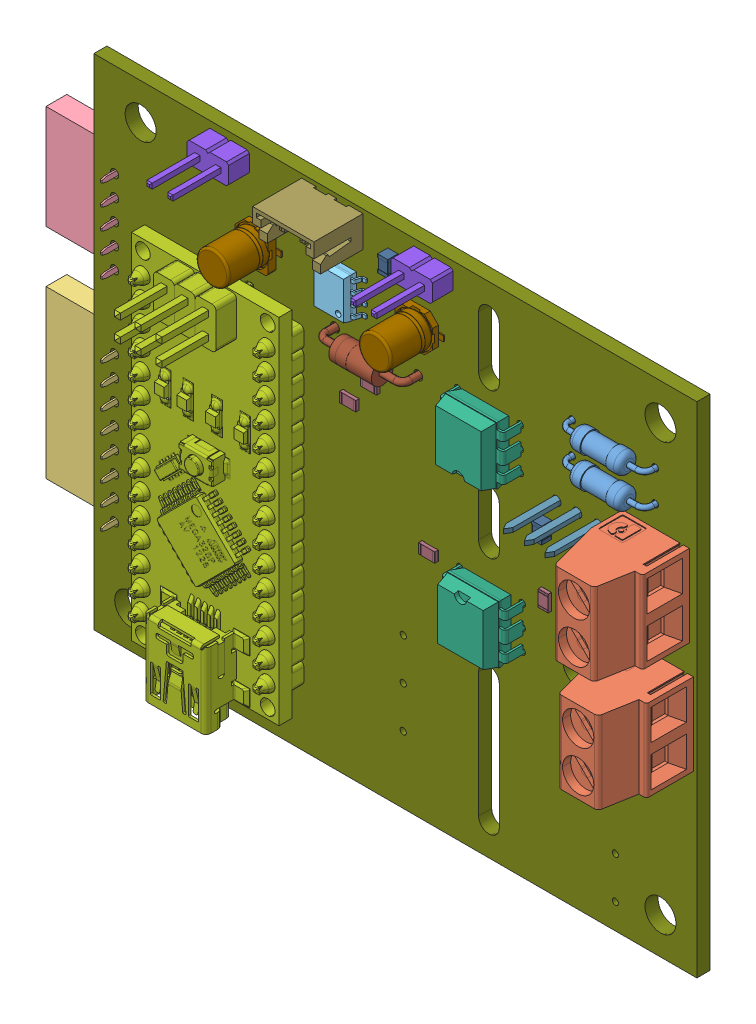
SolidWorks assembly ReflowControllerREV1, configuration Default. Lengths in mm.
Overall size (81.15 60.96 18.6).
74 component instances, 16 part files, 0 mates.
Components (placement in the parent):
- ReflowControllerREV1.step-1: ReflowControllerREV1.step [Default] at origin size (81.15 60.96 18.6)
  - R_Axial_DIN0207_L6.3mm_D2.5mm_P10.16mm_Horizontal.step-1: R_Axial_DIN0207_L6.3mm_D2.5mm_P10.16mm_Horizontal.step [Default] at (251.46 -86.995 1.65) x (-1 0 0) z (0 0 1) size (10.76 2.5 5.5)
    - SOLID.step-1: SOLID.step [Default] at origin size (10.76 2.5 5.5)
  - R_Axial_DIN0207_L6.3mm_D2.5mm_P10.16mm_Horizontal.step-2: R_Axial_DIN0207_L6.3mm_D2.5mm_P10.16mm_Horizontal.step [Default] at (251.46 -83.185 1.65) x (-1 0 0) z (0 0 1) size (10.76 2.5 5.5)
    - SOLID.step-1: SOLID.step [Default] at origin size (10.76 2.5 5.5)
  - Terminal5mmx2.step-1: Terminal5mmx2.step [Default] at (255.095 -100.155 1.65) x (1 0 0) z (0 -1 0) size (8.15 13.5 10.57)
    - SOLID-0.step-1: SOLID-0.step [Default] at origin size (8.15 13.5 10.57)
  - Terminal5mmx2.step-2: Terminal5mmx2.step [Default] at (255.595 -113.49 1.65) x (1 0 0) z (0 -1 0) size (8.15 13.5 10.57)
    - SOLID-0.step-1: SOLID-0.step [Default] at origin size (8.15 13.5 10.57)
  - PinSocket_1x08_P2.54mm_Horizontal.step-1: PinSocket_1x08_P2.54mm_Horizontal.step [Default] at (185.42 -121.92 -0.05) x (1 0 0) z (0 0 -1) size (10.13 20.32 5.84)
    - SOLID-1.step-1: SOLID-1.step [Default] at origin size (10.13 20.32 5.84)
  - PinSocket_1x05_P2.54mm_Horizontal.step-1: PinSocket_1x05_P2.54mm_Horizontal.step [Default] at (185.42 -95.25 -0.05) x (1 0 0) z (0 0 -1) size (10.13 12.7 5.84)
    - SOLID-2.step-1: SOLID-2.step [Default] at origin size (10.13 12.7 5.84)
  - SOIC-8_3,9x4,9.step-1: SOIC-8_3,9x4,9.step [Default] at (213.36 -82.804 1.65) x (0 1 0) z (0 0 1) size (4.9 6 1.75)
    - SOLID-3.step-1: SOLID-3.step [Default] at origin size (4.9 6 1.75)
  - DIP-6_W7.62mm.step-1: DIP-6_W7.62mm.step [Default] at (234.95 -91.948 1.65) x (-1 0 0) z (0 0 1) size (7.87 7.05 6.98)
    - SOLID-4.step-1: SOLID-4.step [Default] at origin size (7.87 7.05 6.98)
  - Arduino_nano.step-1: Arduino_nano.step [Default] at (192.024 -90.932 3.15) x (0 -1 0) z (-1 0 0) size (45.01 18.6 18)
    - COMPOUND.step-1: COMPOUND.step [Default] at origin size (45.01 18.6 18)
  - PinHeader_1x02_P2.54mm_Vertical.step-1: PinHeader_1x02_P2.54mm_Vertical.step [Default] at (198.12 -75.692 1.65) x (0 1 0) z (0 0 1) size (2.54 5.08 11.54)
    - SOLID-5.step-1: SOLID-5.step [Default] at origin size (2.54 5.08 11.54)
  - C_Elec_4x5.8.step-1: C_Elec_4x5.8.step [Default] at (203.2 -83.312 1.65) size (5.74 5.46 5.8)
    - COMPOUND-6.step-1: COMPOUND-6.step [Default] at origin size (5.74 5.46 5.8)
  - C_0805_2012Metric.step-1: C_0805_2012Metric.step [Default] at (204.216 -91.948 1.65) x (0 -1 0) z (0 0 1) size (2 1.25 1.25)
    - SOLID-7.step-1: SOLID-7.step [Default] at origin size (2 1.25 1.25)
  - C_0805_2012Metric.step-2: C_0805_2012Metric.step [Default] at (238.252 -96.012 1.65) x (0 1 0) z (0 0 1) size (2 1.25 1.25)
    - SOLID-7.step-1: SOLID-7.step [Default] at origin size (2 1.25 1.25)
  - C_0805_2012Metric.step-3: C_0805_2012Metric.step [Default] at (219.456 -77.216 1.65) x (0 -1 0) z (0 0 1) size (2 1.25 1.25)
    - SOLID-7.step-1: SOLID-7.step [Default] at origin size (2 1.25 1.25)
  - C_Elec_4x5.8.step-2: C_Elec_4x5.8.step [Default] at (223.012 -82.296 1.65) x (-1 0 0) z (0 0 1) size (5.74 5.46 5.8)
    - COMPOUND-6.step-1: COMPOUND-6.step [Default] at origin size (5.74 5.46 5.8)
  - D_DO-41_SOD81_P10.16mm_Horizontal.step-1: D_DO-41_SOD81_P10.16mm_Horizontal.step [Default] at (212.344 -87.884 1.65) size (10.96 2.72 5.71)
    - SOLID-8.step-1: SOLID-8.step [Default] at origin size (10.96 2.72 5.71)
  - DIP-6_W7.62mm.step-2: DIP-6_W7.62mm.step [Default] at (227.584 -105.664 1.65) size (7.87 7.05 6.98)
    - SOLID-4.step-1: SOLID-4.step [Default] at origin size (7.87 7.05 6.98)
  - JST_EH_B2B-EH-A_1x02_P2.50mm_Vertical.step-1: JST_EH_B2B-EH-A_1x02_P2.50mm_Vertical.step [Default] at (210.82 -75.692 1.65) size (7.5 3.8 9.2)
    - SOLID-9.step-1: SOLID-9.step [Default] at origin size (7.5 3.8 9.2)
  - PinHeader_1x02_P2.54mm_Vertical.step-2: PinHeader_1x02_P2.54mm_Vertical.step [Default] at (223.012 -75.692 1.65) x (0 1 0) z (0 0 1) size (2.54 5.08 11.54)
    - SOLID-5.step-1: SOLID-5.step [Default] at origin size (2.54 5.08 11.54)
  - R_0805_2012Metric.step-1: R_0805_2012Metric.step [Default] at (214.376 -94.488 1.65) x (-1 0 0) z (0 0 1) size (2 1.2 0.45)
    - SOLID-10.step-1: SOLID-10.step [Default] at origin size (2 1.2 0.45)
  - R_0805_2012Metric.step-2: R_0805_2012Metric.step [Default] at (216.916 -91.44 1.65) size (2 1.2 0.45)
    - SOLID-10.step-1: SOLID-10.step [Default] at origin size (2 1.2 0.45)
  - R_0805_2012Metric.step-3: R_0805_2012Metric.step [Default] at (241.3 -99.568 1.65) size (2 1.2 0.45)
    - SOLID-10.step-1: SOLID-10.step [Default] at origin size (2 1.2 0.45)
  - R_0805_2012Metric.step-4: R_0805_2012Metric.step [Default] at (238.252 -103.632 1.65) x (0 1 0) z (0 0 1) size (2 1.2 0.45)
    - SOLID-10.step-1: SOLID-10.step [Default] at origin size (2 1.2 0.45)
  - R_0805_2012Metric.step-5: R_0805_2012Metric.step [Default] at (224.028 -105.664 1.65) size (2 1.2 0.45)
    - SOLID-10.step-1: SOLID-10.step [Default] at origin size (2 1.2 0.45)
  - R_0805_2012Metric.step-6: R_0805_2012Metric.step [Default] at (194.945 -117.475 1.65) x (0 1 0) z (0 0 1) size (2 1.2 0.45)
    - SOLID-10.step-1: SOLID-10.step [Default] at origin size (2 1.2 0.45)
  - R_0805_2012Metric.step-7: R_0805_2012Metric.step [Default] at (197.485 -112.395 -0.05) x (1 0 0) z (0 0 -1) size (2 1.2 0.45)
    - SOLID-10.step-1: SOLID-10.step [Default] at origin size (2 1.2 0.45)
  - R_0805_2012Metric.step-8: R_0805_2012Metric.step [Default] at (203.835 -122.555 1.65) x (-1 0 0) z (0 0 1) size (2 1.2 0.45)
    - SOLID-10.step-1: SOLID-10.step [Default] at origin size (2 1.2 0.45)
  - R_0805_2012Metric.step-9: R_0805_2012Metric.step [Default] at (200.66 -119.38 1.65) size (2 1.2 0.45)
    - SOLID-10.step-1: SOLID-10.step [Default] at origin size (2 1.2 0.45)
  - R_0805_2012Metric.step-10: R_0805_2012Metric.step [Default] at (201.168 -104.648 -0.05) x (1 0 0) z (0 0 -1) size (2 1.2 0.45)
    - SOLID-10.step-1: SOLID-10.step [Default] at origin size (2 1.2 0.45)
  - R_0805_2012Metric.step-11: R_0805_2012Metric.step [Default] at (200.66 -110.236 -0.05) x (1 0 0) z (0 0 -1) size (2 1.2 0.45)
    - SOLID-10.step-1: SOLID-10.step [Default] at origin size (2 1.2 0.45)
  - R_0805_2012Metric.step-12: R_0805_2012Metric.step [Default] at (197.485 -123.19 -0.05) x (-1 0 0) z (0 0 -1) size (2 1.2 0.45)
    - SOLID-10.step-1: SOLID-10.step [Default] at origin size (2 1.2 0.45)
  - R_0805_2012Metric.step-13: R_0805_2012Metric.step [Default] at (195.58 -128.905 -0.05) x (0 -1 0) z (0 0 -1) size (2 1.2 0.45)
    - SOLID-10.step-1: SOLID-10.step [Default] at origin size (2 1.2 0.45)
  - R_0805_2012Metric.step-14: R_0805_2012Metric.step [Default] at (196.215 -114.3 1.65) size (2 1.2 0.45)
    - SOLID-10.step-1: SOLID-10.step [Default] at origin size (2 1.2 0.45)
  - R_0805_2012Metric.step-15: R_0805_2012Metric.step [Default] at (200.66 -115.316 -0.05) x (1 0 0) z (0 0 -1) size (2 1.2 0.45)
    - SOLID-10.step-1: SOLID-10.step [Default] at origin size (2 1.2 0.45)
  - TO-220-3_Horizontal_TabUp.step-1: TO-220-3_Horizontal_TabUp.step [Default] at (244.475 -92.71 -0.05) x (-1 0 0) z (0 0 -1) size (10.25 19.74 12.58)
    - SOLID-11.step-1: SOLID-11.step [Default] at origin size (10.25 19.74 12.58)
  - TO-263-3_TabPin4.step-1: TO-263-3_TabPin4.step [Default] at (218.44 -99.06 -0.05) x (0 -1 0) z (0 0 -1) size (15 10 4.42)
    - SOLID-12.step-1: SOLID-12.step [Default] at origin size (15 10 4.42)
  - COMPOUND-13.step-1: COMPOUND-13.step [Default] at origin size (73.66 60.96 1.6)
